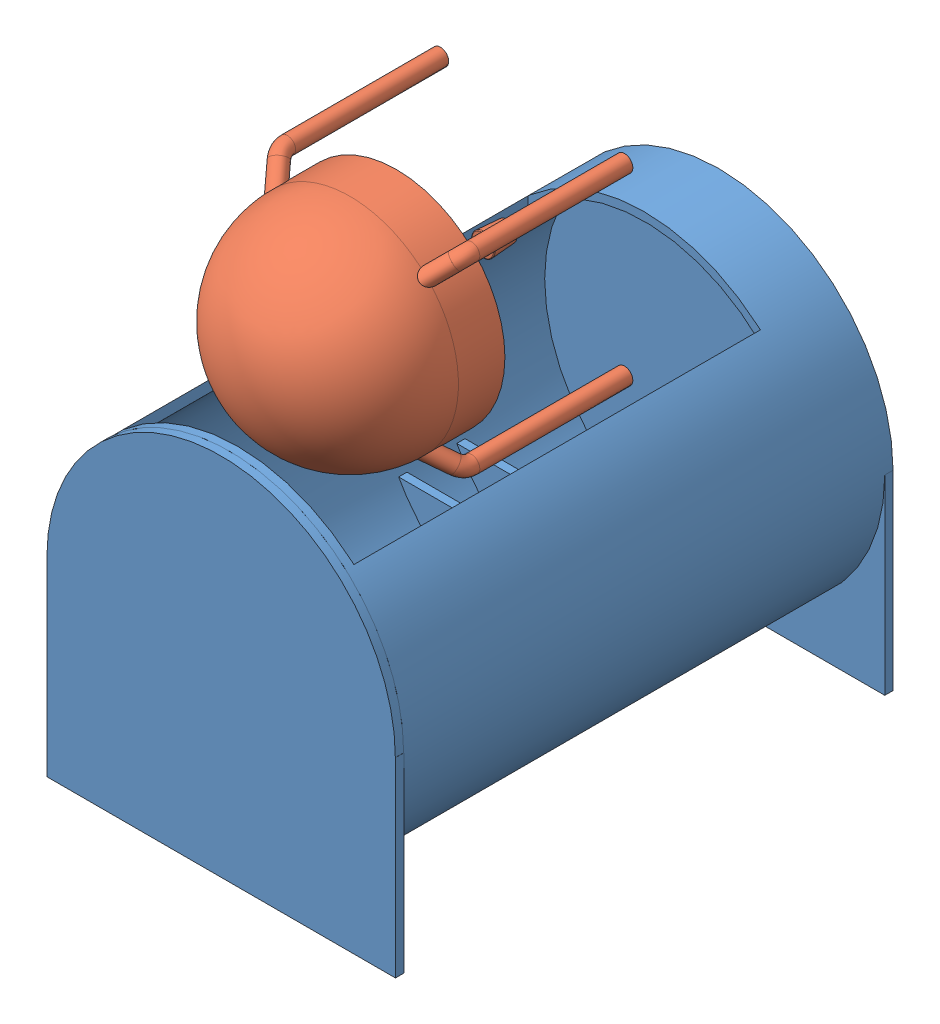
SolidWorks assembly FullPhantom, configuration Default. Lengths in mm.
Overall size (236.12 369.3 330).
2 component instances, 2 part files, 0 mates.
Components (placement in the parent):
- CerebContainer-1: CerebContainer [Default] at (141.265 192.3221 407.1187) size (210.07 220 330)
- CerebDesign-4: CerebDesign [Default] at (141.2135 328.5608 334.3937) x (0.707107 0.707107 0) z (0.707107 -0.707107 0) size (166.96 175.36 166.96)
